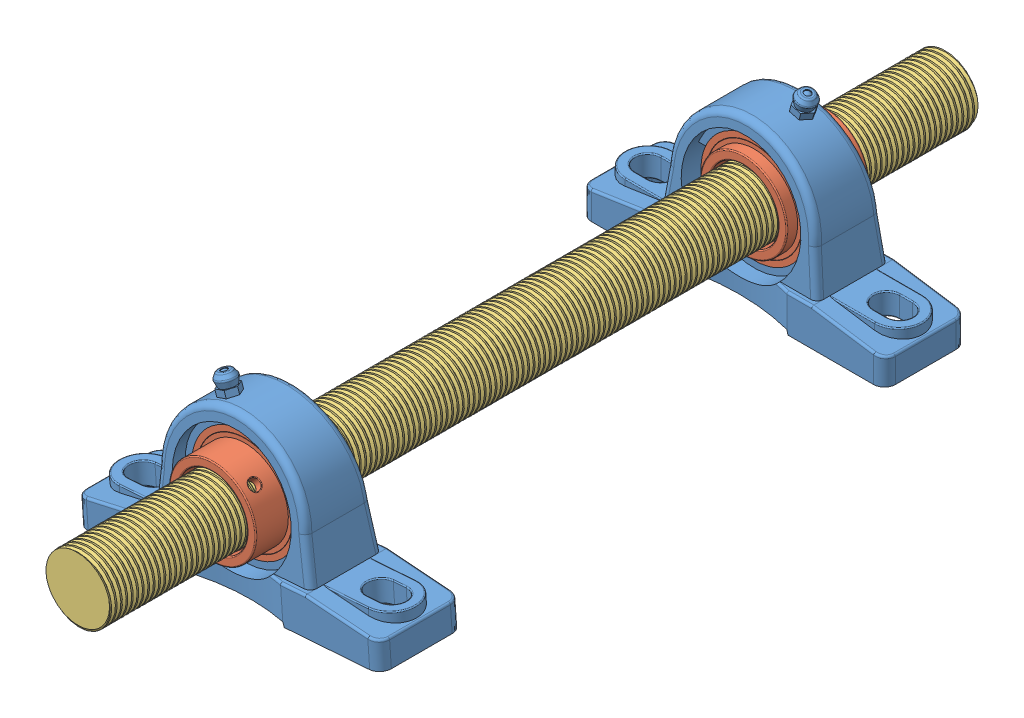
SolidWorks assembly Montaj1, configuration Varsayılan. Lengths in mm.
Overall size (145.29 88.15 406.25).
7 component instances, 3 part files, 2 mates.
Components (placement in the parent):
- rulman_montaj-1: rulman_montaj [Varsayılan] at (-0.8737 -3.0579 2.5) size (140 78.23 43.15)
  - rulman_ana_parça-1: rulman_ana_parça [Varsayılan] at (-14.4158 -17.7259 139.9246) size (140 78.23 38.3)
  - rulman_iç_kısım-1: rulman_iç_kısım [Varsayılan] at (-14.4181 10.2741 139.9246) x (0 0 1) z (0.973203 -0.229946 0) size (38 50.56 50.56)
- rulman_mili-1: rulman_mili [Varsayılan] at (-15.2917 7.2162 63.2852) x (0.410922 0.911671 0) z (0 0 1) size (30.14 34.81 406.25)
- rulman_montaj-2: rulman_montaj [Varsayılan] at (-28.9287 -4.0741 516.9164) x (-0.99738 -0.072347 0) z (0 0 -1) size (140 78.23 43.15)
  - rulman_ana_parça-1: rulman_ana_parça [Varsayılan] at (-14.4158 -17.7259 139.9246) size (140 78.23 38.3)
  - rulman_iç_kısım-1: rulman_iç_kısım [Varsayılan] at (-14.4181 10.2741 139.9246) x (0 0 1) z (0.973203 -0.229946 0) size (38 50.56 50.56)
Mates (geometry in assembly coordinates):
- Çakışık1: coincident: rulman_montaj-1, rulman_mili-1
- Çakışık2: coincident: rulman_mili-1, rulman_montaj-2
